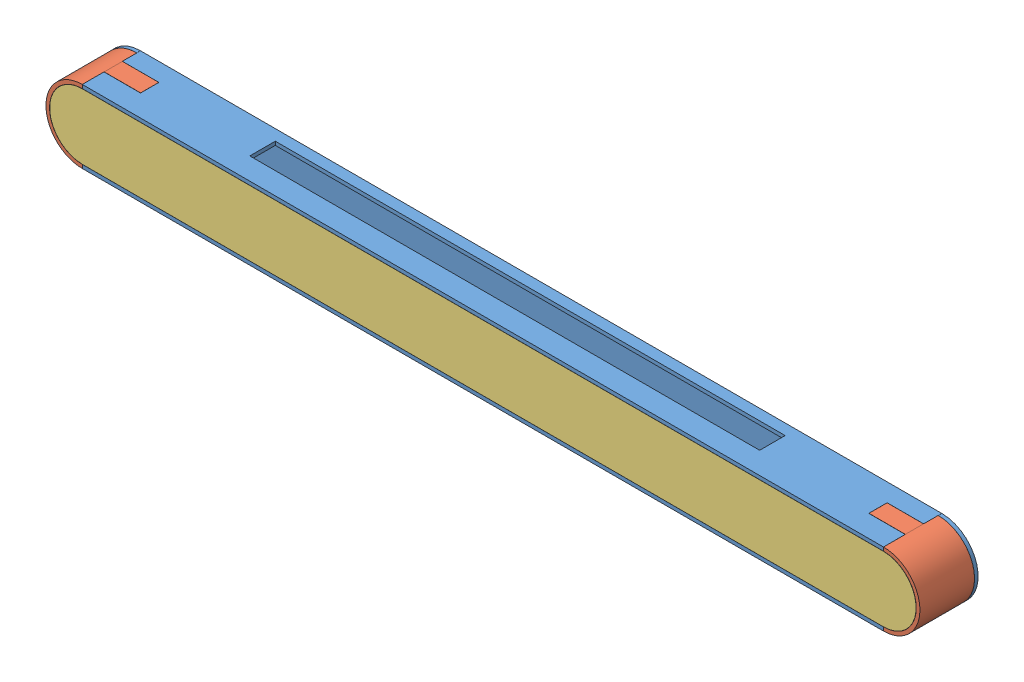
SolidWorks assembly frame - Copy, configuration Default. Lengths in mm.
Overall size (1200 100 80.05).
4 component instances, 3 part files, 8 mates.
Components (placement in the parent):
- joint-1: joint [Default] at (204.0141 760.523 893.6313) size (1200 100 80)
- joint-sides-1: joint-sides [Default] at (203.9641 760.523 893.5813) size (100 100 75)
- joint-sides-2: joint-sides [Default] at (298.6966 760.523 893.6813) x (-1 0 0) z (0 0 1) size (100 100 75)
- diffuser-2: diffuser [Default] at (57.9364 760.523 970.6813) size (1189.6 89.8 3)
Mates (geometry in assembly coordinates):
- Distance2: distance = 0.05 mm anti-aligned: plane of joint-1 through (-248.5196 710.523 943.8313) normal (-1 0 0); plane of joint-sides-2 through (-248.5696 760.523 893.6813) normal (1 0 0)
- Distance4: distance = 0.05 mm anti-aligned: plane of joint-sides-2 through (-248.5696 805.523 918.6813) normal (0 0 -1); plane of joint-1 through (-248.7196 810.523 918.6313) normal (0 0 1)
- Tangent4: tangent aligned: plane of joint-1 through (-298.7196 810.523 973.6313) normal (0 1 0); cylinder of joint-sides-2 through (-298.5696 760.523 973.6813) axis (0 0 -1) radius 50
- Distance6: distance = 0.05 mm anti-aligned: plane of joint-sides-1 through (751.2304 760.523 893.5813) normal (-1 0 0); plane of joint-1 through (751.1804 710.523 918.5313) normal (1 0 0)
- Distance7: distance = 0.05 mm anti-aligned: plane of joint-sides-1 through (751.2304 810.523 918.5813) normal (0 0 -1); plane of joint-1 through (751.1804 710.523 918.5313) normal (0 0 1)
- Coincident10: coincident aligned: plane of joint-1 through (-298.7196 810.523 973.6313) normal (0 1 0); plane of joint-sides-1 through (751.2304 810.523 918.5813) normal (0 1 0)
- Coincident11: coincident anti-aligned: plane of joint-sides-2 through (-298.5696 805.523 970.6813) normal (0 0 1); plane of diffuser-2 through (-298.5696 760.523 970.6813) normal (0 0 -1)
- Concentric1: concentric aligned: cylinder of joint-sides-2 through (-298.5696 760.523 973.6813) axis (0 0 -1) radius 45; cylinder of diffuser-2 through (-298.5696 760.523 973.6813) axis (0 0 -1) radius 44.9
